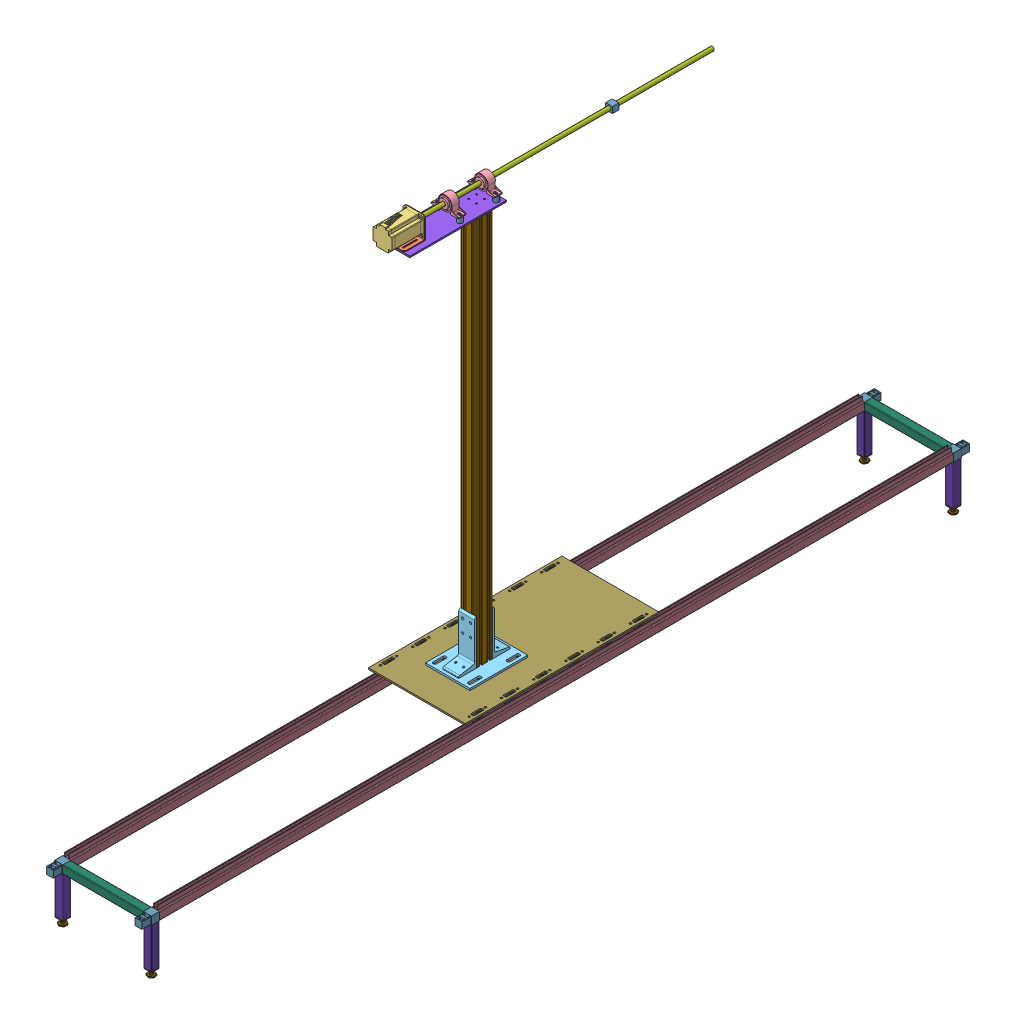
SolidWorks assembly force_analysis, configuration Default. Lengths in mm.
Overall size (312.86 1545.03 2606.68).
75 component instances, 19 part files, 128 mates.
Components (placement in the parent):
- spacer-1: spacer [Default] at (1532.3031 2818.8735 -405.2345) size (16 16.75 16)
- Nema 23_Steel Mounting-1: Nema 23_Steel Mounting [Default] at (1528.9059 2818.8735 -300.1921) x (0 0 1) z (-1 0 0) size (68 68 65)
- 425oz stepper motor-1: 425oz stepper motor [Default] at (1526.3859 2887.8535 -292.1921) x (0 -1 0) z (0 0 -1) size (70.41 60 124)
- 5913K610_LOW-PROFILE MOUNTED BALL BRNG-1: 5913K610_LOW-PROFILE MOUNTED BALL BRNG [5913K61] at (1496.3859 2857.8535 -519.3351) size (85.72 43.66 28.58)
- 25_2387-1: 25_2387 [Default] at (1496.3859 1564.111 -493.3565) x (0 0 -1) z (1 0 0) size (182 146 140)
  - _25_2387_b_2-1: _25_2387_b_2 [Default] at origin size (182 146 140)
  - _M6x1_0_12_s_4-1: _M6x1_0_12_s_4 [Default] at (-53.2 -2.7 12.5) x (0 1 0) z (-1 0 0) size (12 12 12)
  - _M6x1_0_12_s_4-2: _M6x1_0_12_s_4 [Default] at (53.2 -2.7 12.5) x (0 1 0) z (-1 0 0) size (12 12 12)
  - _M6x1_0_12_s_4-3: _M6x1_0_12_s_4 [Default] at (-53.2 -2.7 -12.5) x (0 1 0) z (-1 0 0) size (12 12 12)
  - _M6x1_0_12_s_4-4: _M6x1_0_12_s_4 [Default] at (53.2 -2.7 -12.5) x (0 1 0) z (-1 0 0) size (12 12 12)
- shaft-1: shaft [Default] at (1496.3859 2857.8535 -1235.5921) x (-0.174348 -0.984684 0) z (-0.984684 0.174348 0) size (12.7 914.4 12.7)
- top_plate-2: top_plate [Default] at (1572.5859 2814.111 -232.1921) x (0 0 -1) z (1 0 0) size (304.8 4.76 101.6)
- spacer-2: spacer [Default] at (1460.4687 2818.8735 -405.2345) size (16 16.75 16)
- stand-1: stand [Default] at (1496.3859 3064.111 -493.5565) x (1 0 0) z (0 1 0) size (50 50 1250)
- spacer-3: spacer [Default] at (1532.3031 2818.8735 -519.3351) x (0.999918 0 -0.012814) z (0.012814 0 0.999918) size (16 16.75 16)
- spacer-4: spacer [Default] at (1460.4687 2818.8735 -519.3351) size (16 16.75 16)
- 5913K610_LOW-PROFILE MOUNTED BALL BRNG-2: 5913K610_LOW-PROFILE MOUNTED BALL BRNG [5913K61] at (1496.3859 2857.8535 -405.2345) size (85.72 43.66 28.58)
- Assem3-1: Assem3 [Default] at (1323.2937 1498.0887 -482.7187) x (0 0 1) z (0 1 0) size (63.5 7.14 34.93)
  - slot-1: slot [Default] at (25.1623 33.3922 53.9263) size (63.5 7.14 14.8)
  - wheel-1: wheel [Default] at (25.1623 35.3766 44.1385) x (0 -1 0) z (-0.173033 0 0.984916) size (7.14 30.16 30.16)
- Assem3-2: Assem3 [Default] at (1602.6937 1498.0887 -889.1187) x (0 0 1) z (0 1 0) size (63.5 7.14 34.93)
  - slot-1: slot [Default] at (25.1623 33.3922 53.9263) size (63.5 7.14 14.8)
  - wheel-1: wheel [Default] at (25.1623 35.3766 44.1385) x (0 -1 0) z (-0.173033 0 0.984916) size (7.14 30.16 30.16)
- Assem3-3: Assem3 [Default] at (1323.2937 1498.0887 -889.1187) x (0 0 1) z (0 1 0) size (63.5 7.14 34.93)
  - slot-1: slot [Default] at (25.1623 33.3922 53.9263) size (63.5 7.14 14.8)
  - wheel-1: wheel [Default] at (25.1623 35.3766 44.1385) x (0 -1 0) z (-0.173033 0 0.984916) size (7.14 30.16 30.16)
- Assem3-4: Assem3 [Default] at (1323.2937 1498.0887 -584.3187) x (0 0 1) z (0 1 0) size (63.5 7.14 34.93)
  - slot-1: slot [Default] at (25.1623 33.3922 53.9263) size (63.5 7.14 14.8)
  - wheel-1: wheel [Default] at (25.1623 35.3766 44.1385) x (0 -1 0) z (-0.173033 0 0.984916) size (7.14 30.16 30.16)
- Assem3-5: Assem3 [Default] at (1323.2937 1498.0887 -787.5187) x (0 0 1) z (0 1 0) size (63.5 7.14 34.93)
  - slot-1: slot [Default] at (25.1623 33.3922 53.9263) size (63.5 7.14 14.8)
  - wheel-1: wheel [Default] at (25.1623 35.3766 44.1385) x (0 -1 0) z (-0.173033 0 0.984916) size (7.14 30.16 30.16)
- Assem3-6: Assem3 [Default] at (1323.2937 1498.0887 -685.9187) x (0 0 1) z (0 1 0) size (63.5 7.14 34.93)
  - slot-1: slot [Default] at (25.1623 33.3922 53.9263) size (63.5 7.14 14.8)
  - wheel-1: wheel [Default] at (25.1623 35.3766 44.1385) x (0 -1 0) z (-0.173033 0 0.984916) size (7.14 30.16 30.16)
- Assem3-7: Assem3 [Default] at (1323.2937 1498.0887 -381.1187) x (0 0 1) z (0 1 0) size (63.5 7.14 34.93)
  - slot-1: slot [Default] at (25.1623 33.3922 53.9263) size (63.5 7.14 14.8)
  - wheel-1: wheel [Default] at (25.1623 35.3766 44.1385) x (0 -1 0) z (-0.173033 0 0.984916) size (7.14 30.16 30.16)
- plate-1: plate [Default] at (1648.7859 1553.285 -305.1565) x (0 0 -1) z (1 0 0) size (609.6 4.83 304.8)
- Assem3-8: Assem3 [Default] at (1602.6937 1498.0887 -685.9187) x (0 0 1) z (0 1 0) size (63.5 7.14 34.93)
  - slot-1: slot [Default] at (25.1623 33.3922 53.9263) size (63.5 7.14 14.8)
  - wheel-1: wheel [Default] at (25.1623 35.3766 44.1385) x (0 -1 0) z (-0.173033 0 0.984916) size (7.14 30.16 30.16)
- Assem3-9: Assem3 [Default] at (1602.6937 1498.0887 -787.5187) x (0 0 1) z (0 1 0) size (63.5 7.14 34.93)
  - slot-1: slot [Default] at (25.1623 33.3922 53.9263) size (63.5 7.14 14.8)
  - wheel-1: wheel [Default] at (25.1623 35.3766 44.1385) x (0 -1 0) z (-0.173033 0 0.984916) size (7.14 30.16 30.16)
- Assem3-10: Assem3 [Default] at (1602.6937 1498.0887 -584.3187) x (0 0 1) z (0 1 0) size (63.5 7.14 34.93)
  - slot-1: slot [Default] at (25.1623 33.3922 53.9263) size (63.5 7.14 14.8)
  - wheel-1: wheel [Default] at (25.1623 35.3766 44.1385) x (0 -1 0) z (-0.173033 0 0.984916) size (7.14 30.16 30.16)
- Assem3-11: Assem3 [Default] at (1602.6937 1498.0887 -482.7187) x (0 0 1) z (0 1 0) size (63.5 7.14 34.93)
  - slot-1: slot [Default] at (25.1623 33.3922 53.9263) size (63.5 7.14 14.8)
  - wheel-1: wheel [Default] at (25.1623 35.3766 44.1385) x (0 -1 0) z (-0.173033 0 0.984916) size (7.14 30.16 30.16)
- Assem3-12: Assem3 [Default] at (1602.6937 1498.0887 -381.1187) x (0 0 1) z (0 1 0) size (63.5 7.14 34.93)
  - slot-1: slot [Default] at (25.1623 33.3922 53.9263) size (63.5 7.14 14.8)
  - wheel-1: wheel [Default] at (25.1623 35.3766 44.1385) x (0 -1 0) z (-0.173033 0 0.984916) size (7.14 30.16 30.16)
- bottom-1: bottom [Default] at (1356.678 1514.446 1840.6545) x (0 -1 0) z (0 0 1) size (38.1 25.4 2500)
- 4_prong-1: 4_prong [Default] at (1636.078 1514.446 -1855.0455) x (0 0 -1) z (-1 0 0) size (81.28 53.34 53.34)
- 4_prong-2: 4_prong [Default] at (1356.678 1514.446 -1855.0455) x (0 0 1) z (1 0 0) size (81.28 53.34 53.34)
- strut-1: strut [Default] at (5052.378 1514.446 -1855.0455) x (0 0 -1) z (1 0 0) size (25.4 25.4 254)
- bottom-2: bottom [Default] at (1636.078 1514.446 1840.6545) x (0 -1 0) z (0 0 1) size (38.1 25.4 2500)
- strut-2: strut [Default] at (5052.378 1514.446 670.3545) x (0 0 -1) z (1 0 0) size (25.4 25.4 254)
- 4_prong-3: 4_prong [Default] at (1636.078 1514.446 670.3545) x (0 0 -1) z (-1 0 0) size (81.28 53.34 53.34)
- 4_prong-4: 4_prong [Default] at (1356.678 1514.446 670.3545) x (0 0 1) z (1 0 0) size (81.28 53.34 53.34)
- end_piece-1: end_piece [Default] at (1356.678 1372.3838 -1855.0455) size (25.4 30.94 25.4)
- down-1: down [Default] at (1356.678 -2181.254 -1855.0455) x (1 0 0) z (0 -1 0) size (25.4 25.4 127)
- foot-1: foot [Default] at (1356.678 1353.2335 -1855.0455) x (0.837169 0 0.546944) z (-0.546944 0 0.837169) size (23.51 54.64 25.19)
- end_piece-2: end_piece [Default] at (1636.078 1372.3838 -1855.0455) size (25.4 30.94 25.4)
- down-2: down [Default] at (1636.078 -2181.254 -1855.0455) x (1 0 0) z (0 -1 0) size (25.4 25.4 127)
- foot-2: foot [Default] at (1636.078 1353.2335 -1855.0455) x (0.837169 0 0.546944) z (-0.546944 0 0.837169) size (23.51 54.64 25.19)
- end_piece-3: end_piece [Default] at (1636.078 1372.3838 670.3545) size (25.4 30.94 25.4)
- down-3: down [Default] at (1636.078 -2181.254 670.3545) x (1 0 0) z (0 -1 0) size (25.4 25.4 127)
- end_piece-4: end_piece [Default] at (1356.678 1372.3838 670.3545) size (25.4 30.94 25.4)
- down-4: down [Default] at (1356.678 -2181.254 670.3545) x (1 0 0) z (0 -1 0) size (25.4 25.4 127)
- foot-3: foot [Default] at (1356.678 1353.2335 670.3545) x (0.997412 0 0.071898) z (-0.071898 0 0.997412) size (23.51 54.64 25.19)
- foot-4: foot [Default] at (1636.078 1353.2335 670.3545) x (0.986144 0 -0.165892) z (0.165892 0 0.986144) size (23.51 54.64 25.19)
- end-1: end [Default] at (1496.3859 2857.8535 -910.7921) x (1 0 0) z (0 1 0) size (21.31 20 19.61)
Mates (geometry in assembly coordinates):
- Concentric15: concentric anti-aligned: circle of plate-1; circle of Assem3-9/slot-1
- Coincident1: coincident anti-aligned: circle of plate-1; circle of Assem3-12/slot-1
- Coincident2: coincident anti-aligned: circle of plate-1; circle of Assem3-11/slot-1
- Coincident3: coincident anti-aligned: circle of plate-1; circle of Assem3-8/slot-1
- Coincident4: coincident anti-aligned: circle of Assem3-7/slot-1; circle of plate-1
- Coincident5: coincident anti-aligned: circle of plate-1; circle of Assem3-9/slot-1
- Coincident6: coincident anti-aligned: circle of Assem3-1/slot-1; circle of plate-1
- Coincident7: coincident anti-aligned: circle of Assem3-1/slot-1; circle of plate-1
- Coincident8: coincident anti-aligned: circle of Assem3-4/slot-1; circle of plate-1
- Coincident9: coincident anti-aligned: circle of Assem3-6/slot-1; circle of plate-1
- Coincident10: coincident anti-aligned: circle of plate-1; circle of Assem3-10/slot-1
- Coincident11: coincident anti-aligned: circle of Assem3-6/slot-1; circle of plate-1
- Coincident12: coincident anti-aligned: circle of Assem3-5/slot-1; circle of plate-1
- Coincident13: coincident anti-aligned: circle of Assem3-4/slot-1; circle of plate-1
- Coincident14: coincident anti-aligned: circle of Assem3-5/slot-1; circle of plate-1
- Coincident15: coincident anti-aligned: circle of plate-1; circle of Assem3-8/slot-1
- Coincident16: coincident anti-aligned: circle of plate-1; circle of Assem3-11/slot-1
- Coincident17: coincident anti-aligned: circle of Assem3-3/slot-1; circle of plate-1
- Coincident18: coincident anti-aligned: circle of Assem3-3/slot-1; circle of plate-1
- Coincident19: coincident anti-aligned: circle of plate-1; circle of Assem3-10/slot-1
- Coincident20: coincident anti-aligned: circle of Assem3-2/slot-1; circle of plate-1
- Coincident21: coincident anti-aligned: circle of Assem3-2/slot-1; circle of plate-1
- Coincident22: coincident anti-aligned: circle of plate-1; circle of Assem3-12/slot-1
- Coincident23: coincident anti-aligned: circle of Assem3-7/slot-1; circle of plate-1
- Coincident55: coincident anti-aligned: circle of top_plate-2; circle of stand-1
- Parallel1: parallel aligned: line of 25_2387-1/_25_2387_b_2-1 through (1426.3859 1558.111 -402.3565) axis (1 0 0); line of plate-1 through (1343.9859 1558.111 -305.1565) axis (1 0 0)
- Coincident59: coincident anti-aligned: plane of 25_2387-1/_25_2387_b_2-1 through (1496.3859 1564.111 -493.3565) normal (0 1 0); plane of stand-1 through (1472.4559 1564.111 -501.7365) normal (0 -1 0)
- Coincident60: coincident aligned: plane of 25_2387-1/_25_2387_b_2-1 through (1471.3859 1698.111 -518.5565) normal (-1 0 0); plane of stand-1 through (1471.3859 2814.111 -485.3765) normal (-1 0 0)
- Parallel2: parallel aligned: line of 25_2387-1/_25_2387_b_2-1 through (1566.3859 1558.111 -402.3565) axis (0 0 -1); line of plate-1 through (1648.7859 1558.111 -305.1565) axis (0 0 -1)
- Coincident67: coincident anti-aligned: plane of 25_2387-1/_25_2387_b_2-1 through (1496.3859 1558.111 -493.3565) normal (0 -1 0); plane of plate-1 through (1648.7859 1558.111 -305.1565) normal (0 1 0)
- Coincident70: coincident anti-aligned: plane of 25_2387-1/_25_2387_b_2-1 through (1521.3859 1704.111 -518.5565) normal (0 0 1); plane of stand-1 through (1488.2059 2814.111 -518.5565) normal (0 0 -1)
- Parallel3: parallel aligned: line of Nema 23_Steel Mounting-1 through (1463.9059 2818.8735 -300.1921) axis (0 0 1); line of 425oz stepper motor-1 through (1466.3859 2841.0535 -287.1921) axis (0 0 1)
- Coincident72: coincident anti-aligned: plane of ? through (1486.8859 2818.8735 -506.0565) normal (0 -1 0); plane of top_plate-2 through (1572.5859 2818.8735 -232.1921) normal (0 1 0)
- Coincident74: coincident aligned: circle of top_plate-2; circle of spacer-4
- Coincident75: coincident anti-aligned: plane of Nema 23_Steel Mounting-1 through (1463.9059 2818.8735 -232.1921) normal (0 -1 0); plane of top_plate-2 through (1572.5859 2818.8735 -232.1921) normal (0 1 0)
- Coincident76: coincident anti-aligned: plane of top_plate-2 through (1572.5859 2818.8735 -232.1921) normal (0 1 0); plane of ? through (1486.8859 2818.8735 -481.0565) normal (0 -1 0)
- Coincident78: coincident anti-aligned: plane of ? through (1447.4687 2814.111 -519.3351) normal (0 1 0); plane of top_plate-2 through (1572.5859 2814.111 -232.1921) normal (0 -1 0)
- Coincident80: coincident anti-aligned: circle of top_plate-2; circle of stand-1
- Coincident83: coincident anti-aligned: plane of ? through (1511.3974 2818.8735 -504.4156) normal (0 -1 0); plane of top_plate-2 through (1572.5859 2818.8735 -232.1921) normal (0 1 0)
- Coincident84: coincident anti-aligned: plane of ? through (1511.8859 2818.8735 -481.0565) normal (0 -1 0); plane of top_plate-2 through (1572.5859 2818.8735 -232.1921) normal (0 1 0)
- Coincident85: coincident aligned: line of Nema 23_Steel Mounting-1 through (1469.9059 2818.8735 -232.1921) axis (1 0 0); line of top_plate-2 through (1445.5859 2818.8735 -232.1921) axis (1 0 0)
- Coincident87: coincident anti-aligned: plane of 5913K610_LOW-PROFILE MOUNTED BALL BRNG-1 through (1472.4147 2838.8035 -413.1284) normal (0 1 0); plane of ? through (1462.6565 2838.8035 -515.9864) normal (0 -1 0)
- Coincident88: coincident aligned: circle of top_plate-2; circle of spacer-2
- Coincident90: coincident anti-aligned: plane of ? through (1525.1928 2814.111 -508.4519) normal (0 1 0); plane of top_plate-2 through (1572.5859 2814.111 -232.1921) normal (0 -1 0)
- Parallel4: parallel anti-aligned: plane of 425oz stepper motor-1 through (1522.3859 2827.8535 -297.1921) normal (0 -1 0); plane of top_plate-2 through (1572.5859 2818.8735 -232.1921) normal (0 1 0)
- Coincident95: coincident aligned: plane of shaft-1 through (1496.3859 2857.8535 -340.3961) normal (0 0 1); plane of ? through (1496.3859 2857.8535 -340.3961) normal (0 0 1)
- Coincident96: coincident aligned: circle of spacer-1; circle of top_plate-2
- Coincident101: coincident aligned: plane of 425oz stepper motor-1 through (1496.3859 2857.8535 -321.1921) normal (0 0 -1); plane of ? through (1496.3859 2857.8535 -321.1921) normal (0 0 -1)
- Coincident102: coincident anti-aligned: plane of Nema 23_Steel Mounting-1 through (1463.9059 2886.8735 -297.1921) normal (0 0 1); plane of 425oz stepper motor-1 through (1522.3859 2883.8535 -297.1921) normal (0 0 -1)
- Parallel5: parallel aligned: line of Nema 23_Steel Mounting-1 through (1469.9059 2818.8735 -232.1921) axis (1 0 0); line of 425oz stepper motor-1 through (1479.5859 2827.8535 -197.1921) axis (1 0 0)
- Coincident103: coincident aligned: circle of top_plate-2; circle of spacer-3
- Coincident104: coincident anti-aligned: plane of spacer-1 through (1532.3031 2835.6285 -405.2345) normal (0 1 0); plane of 5913K610_LOW-PROFILE MOUNTED BALL BRNG-2 through (1516.4837 2835.6285 -392.9313) normal (0 -1 0)
- Coincident105: coincident anti-aligned: plane of 5913K610_LOW-PROFILE MOUNTED BALL BRNG-1 through (1539.2484 2838.8035 -413.1284) normal (0 1 0); plane of ? through (1532.3031 2838.8035 -523.3351) normal (0 -1 0)
- Concentric50: concentric aligned: cylinder of ? through (1532.3031 2832.3486 -519.3351) axis (0 -1 0) radius 4; cylinder of top_plate-2 through (1532.3031 2818.8735 -519.3351) axis (0 -1 0) radius 4.05
- Concentric53: concentric aligned: circle of Nema 23_Steel Mounting-1; circle of 425oz stepper motor-1
- Concentric54: concentric anti-aligned: cylinder of shaft-1 through (1496.3859 2857.8535 -340.3961) axis (0 0 -1) radius 6.35; cylinder of ? through (1496.3859 2857.8535 -349.7941) axis (0 0 1) radius 6.35
- Concentric55: concentric anti-aligned: cylinder of 425oz stepper motor-1 through (1496.3859 2857.8535 -321.1921) axis (0 0 1) radius 3.175; cylinder of shaft-1 through (1496.3859 2857.8535 -366.506) axis (0 0 -1) radius 6.35
- Concentric56: concentric anti-aligned: cylinder of 5913K610_LOW-PROFILE MOUNTED BALL BRNG-1 through (1496.3859 2857.8535 -525.0622) axis (0 0 1) radius 6.35; cylinder of shaft-1 through (1496.3859 2857.8535 -366.506) axis (0 0 -1) radius 6.35
- Concentric57: concentric aligned: circle of 5913K610_LOW-PROFILE MOUNTED BALL BRNG-1; circle of spacer-3
- Concentric58: concentric aligned: cylinder of 5913K610_LOW-PROFILE MOUNTED BALL BRNG-1 through (1532.3031 2835.6285 -519.3351) axis (0 1 0) radius 4.3656; cylinder of ? through (1532.3031 2843.2035 -519.3351) axis (0 1 0) radius 7
- Concentric59: concentric aligned: cylinder of 5913K610_LOW-PROFILE MOUNTED BALL BRNG-1 through (1460.4687 2835.6285 -519.3351) axis (0 1 0) radius 4.3656; cylinder of ? through (1460.4687 2843.2035 -519.3351) axis (0 1 0) radius 7
- Concentric61: concentric anti-aligned: cylinder of 5913K610_LOW-PROFILE MOUNTED BALL BRNG-1 through (1460.4687 2835.6285 -519.3351) axis (0 1 0) radius 4.3656; cylinder of spacer-4 through (1460.4687 2835.6285 -519.3351) axis (0 -1 0) radius 4.05
- Concentric63: concentric anti-aligned: cylinder of ? through (1508.8859 2848.8735 -481.0565) axis (0 1 0) radius 6; cylinder of top_plate-2 through (1508.8859 2818.8735 -481.0565) axis (0 -1 0) radius 2.5
- Concentric65: concentric anti-aligned: cylinder of 425oz stepper motor-1 through (1496.3859 2857.8535 -321.1921) axis (0 0 1) radius 3.175; cylinder of ? through (1496.3859 2857.8535 -311.7941) axis (0 0 -1) radius 5
- Concentric66: concentric anti-aligned: cylinder of ? through (1483.8859 2848.8735 -506.0565) axis (0 1 0) radius 6; cylinder of top_plate-2 through (1483.8859 2818.8735 -506.0565) axis (0 -1 0) radius 2.5
- Concentric69: concentric anti-aligned: cylinder of top_plate-2 through (1483.8859 2818.8735 -481.0565) axis (0 -1 0) radius 2.5; cylinder of ? through (1483.8859 2848.8735 -481.0565) axis (0 1 0) radius 6
- Concentric70: concentric anti-aligned: cylinder of ? through (1508.8859 2848.8735 -506.0565) axis (0 1 0) radius 6; cylinder of top_plate-2 through (1508.8859 2818.8735 -506.0565) axis (0 -1 0) radius 2.5
- Concentric71: concentric aligned: circle of spacer-1; circle of 5913K610_LOW-PROFILE MOUNTED BALL BRNG-2
- Concentric73: concentric aligned: cylinder of 25_2387-1/_25_2387_b_2-1 through (1551.3859 1558.111 -447.3565) axis (0 -1 0) radius 5.5; cylinder of plate-1 through (1551.3859 1558.111 -447.3565) axis (0 -1 0) radius 4.1
- Concentric76: concentric aligned: cylinder of ? through (1460.4687 2832.3486 -519.3351) axis (0 -1 0) radius 4; cylinder of top_plate-2 through (1460.4687 2818.8735 -519.3351) axis (0 -1 0) radius 4.05
- Coincident112: coincident anti-aligned: plane of ? through (1441.3859 1564.111 -460.3565) normal (0 -1 0); plane of 25_2387-1/_25_2387_b_2-1 through (1496.3859 1564.111 -493.3565) normal (0 1 0)
- Concentric84: concentric anti-aligned: cylinder of ? through (1441.3859 1545.8735 -447.3565) axis (0 1 0) radius 4; cylinder of 25_2387-1/_25_2387_b_2-1 through (1441.3859 1558.111 -447.3565) axis (0 -1 0) radius 5.5
- Concentric92: concentric anti-aligned: cylinder of top_plate-2 through (1483.8859 2818.8735 -481.0565) axis (0 -1 0) radius 2.5; cylinder of ? through (1483.8859 2821.0735 -481.0565) axis (0 1 0) radius 3.8
- Coincident120: coincident anti-aligned: plane of top_plate-2 through (1572.5859 2818.8735 -232.1921) normal (0 1 0); plane of ? through (1485.8859 2818.8735 -481.0565) normal (0 -1 0)
- Concentric93: concentric anti-aligned: cylinder of top_plate-2 through (1483.8859 2818.8735 -506.0565) axis (0 -1 0) radius 2.5; cylinder of ? through (1483.8859 2821.0735 -506.0565) axis (0 1 0) radius 3.8
- Coincident121: coincident anti-aligned: plane of top_plate-2 through (1572.5859 2818.8735 -232.1921) normal (0 1 0); plane of ? through (1485.8859 2818.8735 -506.0565) normal (0 -1 0)
- Concentric94: concentric anti-aligned: cylinder of top_plate-2 through (1508.8859 2818.8735 -506.0565) axis (0 -1 0) radius 2.5; cylinder of ? through (1508.8859 2821.0735 -506.0565) axis (0 1 0) radius 3.8
- Coincident122: coincident anti-aligned: plane of top_plate-2 through (1572.5859 2818.8735 -232.1921) normal (0 1 0); plane of ? through (1510.8859 2818.8735 -506.0565) normal (0 -1 0)
- Concentric95: concentric anti-aligned: cylinder of top_plate-2 through (1508.8859 2818.8735 -481.0565) axis (0 -1 0) radius 2.5; cylinder of ? through (1508.8859 2821.0735 -481.0565) axis (0 1 0) radius 3.8
- Coincident123: coincident anti-aligned: plane of top_plate-2 through (1572.5859 2818.8735 -232.1921) normal (0 1 0); plane of ? through (1507.2116 2818.8735 -482.1504) normal (0 -1 0)
- Concentric96: concentric anti-aligned: circle of end_piece-2; cylinder of foot-2 through (1636.078 1408.1784 -1855.0455) axis (0 -1 0) radius 4.7625
- Concentric97: concentric anti-aligned: circle of end_piece-4; cylinder of foot-3 through (1356.678 1408.1784 670.3545) axis (0 -1 0) radius 4.7625
- Coincident124: coincident aligned: line of bottom-1 through (1343.978 1503.8542 657.6545) axis (0 1 0); line of 4_prong-4 through (1343.978 1501.746 657.6545) axis (0 1 0)
- Coincident125: coincident aligned: line of 4_prong-1 through (1623.378 1527.146 -1842.3455) axis (1 0 0); line of bottom-2 through (1631.633 1527.146 -1842.3455) axis (1 0 0)
- Coincident126: coincident anti-aligned: line of 4_prong-1 through (1623.378 1527.146 -1867.7455) axis (0 0 1); line of strut-1 through (1623.378 1527.146 -1844.4537) axis (0 0 -1)
- Coincident127: coincident anti-aligned: line of 4_prong-1 through (1623.378 1501.746 -1867.7455) axis (0 1 0); line of strut-1 through (1623.378 1525.0378 -1867.7455) axis (0 -1 0)
- Coincident128: coincident anti-aligned: line of strut-2 through (1623.378 1527.146 680.9463) axis (0 0 -1); line of 4_prong-3 through (1623.378 1527.146 657.6545) axis (0 0 1)
- Coincident129: coincident aligned: line of 4_prong-2 through (1369.378 1527.146 -1842.3455) axis (0 0 -1); line of strut-1 through (1369.378 1527.146 -1844.4537) axis (0 0 -1)
- Coincident130: coincident anti-aligned: line of bottom-2 through (1625.4862 1527.146 657.6545) axis (1 0 0); line of 4_prong-3 through (1648.778 1527.146 657.6545) axis (-1 0 0)
- Coincident131: coincident anti-aligned: line of 4_prong-1 through (1648.778 1501.746 -1842.3455) axis (0 1 0); line of bottom-2 through (1648.778 1525.0378 -1842.3455) axis (0 -1 0)
- Coincident132: coincident anti-aligned: line of bottom-1 through (1352.233 1527.146 657.6545) axis (1 0 0); line of 4_prong-4 through (1369.378 1527.146 657.6545) axis (-1 0 0)
- Coincident133: coincident anti-aligned: line of strut-2 through (1623.378 1525.0378 657.6545) axis (0 -1 0); line of 4_prong-3 through (1623.378 1501.746 657.6545) axis (0 1 0)
- Coincident134: coincident anti-aligned: line of bottom-1 through (1343.978 1503.8542 -1842.3455) axis (0 1 0); line of 4_prong-2 through (1343.978 1527.146 -1842.3455) axis (0 -1 0)
- Coincident135: coincident anti-aligned: line of bottom-2 through (1623.378 1503.8542 657.6545) axis (0 1 0); line of strut-2 through (1623.378 1525.0378 657.6545) axis (0 -1 0)
- Coincident136: coincident aligned: line of strut-2 through (1369.378 1527.146 680.9463) axis (0 0 -1); line of 4_prong-4 through (1369.378 1527.146 683.0545) axis (0 0 -1)
- Coincident137: coincident aligned: line of end_piece-3 through (1625.4862 1374.746 683.0545) axis (1 0 0); line of down-3 through (1625.4862 1374.746 683.0545) axis (1 0 0)
- Coincident138: coincident anti-aligned: line of 4_prong-4 through (1343.978 1501.746 683.0545) axis (0 0 -1); line of down-4 through (1343.978 1501.746 659.7627) axis (0 0 1)
- Coincident139: coincident anti-aligned: line of 4_prong-3 through (1648.778 1501.746 683.0545) axis (-1 0 0); line of down-3 through (1625.4862 1501.746 683.0545) axis (1 0 0)
- Coincident140: coincident aligned: line of end_piece-2 through (1623.378 1374.746 -1865.6373) axis (0 0 1); line of down-2 through (1623.378 1374.746 -1865.6373) axis (0 0 1)
- Coincident141: coincident anti-aligned: line of 4_prong-1 through (1648.778 1501.746 -1867.7455) axis (0 0 1); line of down-2 through (1648.778 1501.746 -1844.4537) axis (0 0 -1)
- Coincident142: coincident aligned: line of end_piece-3 through (1623.378 1374.746 659.7627) axis (0 0 1); line of down-3 through (1623.378 1374.746 659.7627) axis (0 0 1)
- Coincident143: coincident aligned: line of end_piece-1 through (1343.978 1374.746 -1865.6373) axis (0 0 1); line of down-1 through (1343.978 1374.746 -1865.6373) axis (0 0 1)
- Coincident144: coincident anti-aligned: line of strut-1 through (1369.378 1501.746 -1865.6373) axis (0 0 1); line of down-1 through (1369.378 1501.746 -1844.4537) axis (0 0 -1)
- Coincident145: coincident aligned: line of end_piece-4 through (1343.978 1374.746 659.7627) axis (0 0 1); line of down-4 through (1343.978 1374.746 659.7627) axis (0 0 1)
- Coincident146: coincident anti-aligned: line of 4_prong-3 through (1648.778 1501.746 657.6545) axis (0 0 1); line of down-3 through (1648.778 1501.746 680.9463) axis (0 0 -1)
- Coincident147: coincident anti-aligned: plane of end_piece-1 through (1356.678 1372.3838 -1855.0455) normal (0 -1 0); plane of foot-1 through (1362.6586 1372.3838 -1851.1383) normal (0 1 0)
- Coincident148: coincident anti-aligned: plane of end_piece-4 through (1356.678 1372.3838 670.3545) normal (0 -1 0); plane of foot-3 through (1363.8033 1372.3838 670.8681) normal (0 1 0)
- Coincident149: coincident aligned: line of end_piece-2 through (1625.4862 1374.746 -1842.3455) axis (1 0 0); line of down-2 through (1625.4862 1374.746 -1842.3455) axis (1 0 0)
- Coincident150: coincident aligned: line of end_piece-1 through (1346.0862 1374.746 -1842.3455) axis (1 0 0); line of down-1 through (1346.0862 1374.746 -1842.3455) axis (1 0 0)
- Coincident151: coincident anti-aligned: plane of end_piece-2 through (1636.078 1372.3838 -1855.0455) normal (0 -1 0); plane of foot-2 through (1642.0586 1372.3838 -1851.1383) normal (0 1 0)
- Coincident152: coincident anti-aligned: line of 4_prong-2 through (1343.978 1501.746 -1867.7455) axis (1 0 0); line of down-1 through (1367.2698 1501.746 -1867.7455) axis (-1 0 0)
- Coincident153: coincident aligned: line of end_piece-4 through (1346.0862 1374.746 683.0545) axis (1 0 0); line of down-4 through (1346.0862 1374.746 683.0545) axis (1 0 0)
- Concentric98: concentric anti-aligned: circle of end_piece-1; cylinder of foot-1 through (1356.678 1408.1784 -1855.0455) axis (0 -1 0) radius 4.7625
- Coincident154: coincident aligned: line of strut-2 through (1369.378 1503.8542 683.0545) axis (0 1 0); line of 4_prong-4 through (1369.378 1501.746 683.0545) axis (0 1 0)
- Coincident155: coincident anti-aligned: line of 4_prong-4 through (1369.378 1501.746 683.0545) axis (-1 0 0); line of down-4 through (1346.0862 1501.746 683.0545) axis (1 0 0)
- Coincident156: coincident anti-aligned: line of bottom-2 through (1646.6698 1501.746 -1842.3455) axis (-1 0 0); line of down-2 through (1625.4862 1501.746 -1842.3455) axis (1 0 0)
- Tangent1: tangent: circle of Assem3-2/wheel-1; plane of bottom-2 through (1631.633 1527.146 657.6545) normal (0 1 0)
- Tangent2: tangent: circle of Assem3-12/wheel-1; plane of bottom-2 through (1631.633 1527.146 657.6545) normal (0 1 0)
- Tangent3: tangent: circle of Assem3-7/wheel-1; plane of bottom-1 through (1352.233 1527.146 657.6545) normal (0 1 0)
- Tangent4: tangent: circle of Assem3-3/wheel-1; plane of bottom-1 through (1352.233 1527.146 657.6545) normal (0 1 0)
- Distance2: distance = 0.5 mm anti-aligned: plane of Assem3-7/slot-1 through (1353.114 1552.015 -355.9565) normal (-1 0 0); plane of bottom-1 through (1352.614 1539.084 657.6545) normal (1 0 0)
- Distance3: distance = 1597.811 mm anti-aligned: plane of plate-1 through (1343.9859 1558.111 -914.7565) normal (0 0 -1); plane of strut-2 through (1623.378 1503.8542 683.0545) normal (0 0 1)
- Concentric99: concentric aligned: cylinder of end_piece-3 through (1636.078 1372.3838 670.3545) axis (0 -1 0) radius 4.7625; cylinder of foot-4 through (1636.078 1408.1784 670.3545) axis (0 -1 0) radius 4.7625
- Coincident157: coincident anti-aligned: plane of end_piece-3 through (1636.078 1372.3838 670.3545) normal (0 -1 0); plane of foot-4 through (1643.1228 1372.3838 669.1694) normal (0 1 0)
- Concentric100: concentric anti-aligned: cylinder of shaft-1 through (1496.3859 2857.8535 -366.506) axis (0 0 -1) radius 6.35; cylinder of end-1 through (1496.3859 2857.8535 -976.106) axis (0 0 1) radius 6.35
- Distance4: distance = 304.8 mm aligned: plane of end-1 through (1496.3859 2857.8535 -930.7921) normal (0 0 -1); plane of shaft-1 through (1496.3859 2857.8535 -1235.5921) normal (0 0 -1)
- Parallel6: parallel anti-aligned: line of top_plate-2 through (1547.1859 2818.8735 -536.9921) axis (-1 0 0); line of end-1 through (1485.7288 2867.6581 -956.106) axis (1 0 0)
- Coincident160: coincident anti-aligned: plane of 425oz stepper motor-1 through (1496.3859 2857.8535 -321.1921) normal (0 0 -1); plane of shaft-1 through (1496.3859 2857.8535 -321.1921) normal (0 0 1)
